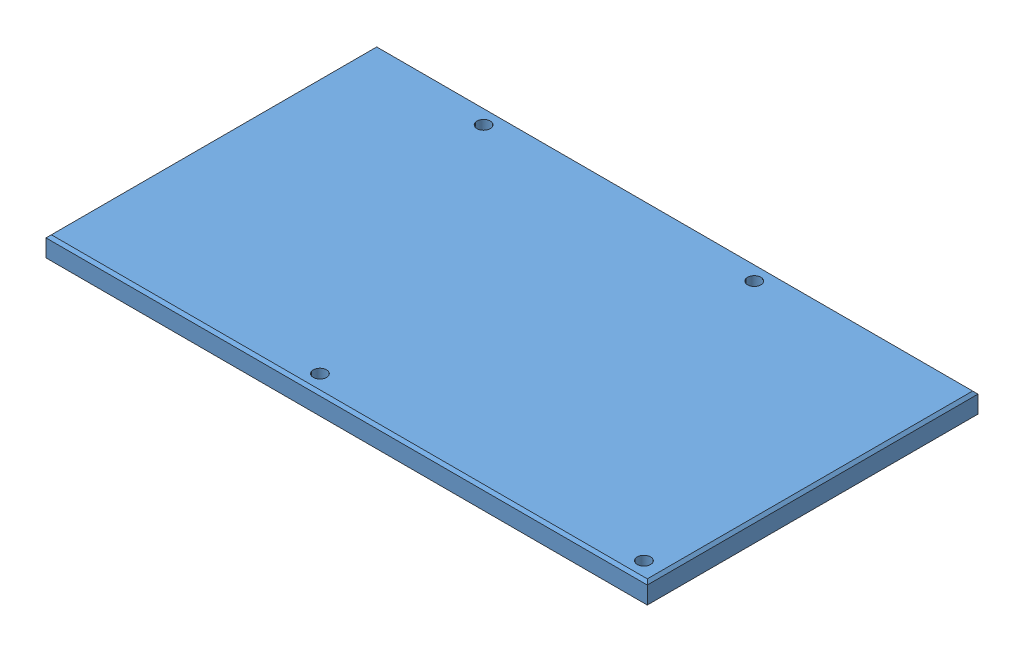
SolidWorks assembly nosilec_napajalnikov, configuration Default. Lengths in mm.
Overall size (180 16 99).
3 component instances, 2 part files, 6 mates.
Components (placement in the parent):
- podstavek_napajalniki-1: podstavek_napajalniki [Default] at (18.8147 123.9174 143.3216) size (180 6 99)
- din_nosilec-1: din_nosilec [Default] at (10.0328 123.9174 164.6273) x (0 0 -1) z (-1 0 0) size (70 10 30)
- din_nosilec-2: din_nosilec [Default] at (100.0328 123.9174 164.6273) x (0 0 -1) z (-1 0 0) size (70 10 30)
Mates (geometry in assembly coordinates):
- Coincident1: coincident anti-aligned: plane of podstavek_napajalniki-1 through (18.8147 123.9174 143.3216) normal (0 -1 0); plane of din_nosilec-1 through (10.0328 123.9174 164.6273) normal (0 1 0)
- Distance1: distance = 14.5 mm aligned: plane of din_nosilec-1 through (15.9698 119.9174 192.8302) normal (0 0 1); plane of podstavek_napajalniki-1 through (-44.0302 129.9174 207.3302) normal (0 0 1)
- Distance3: distance = 30 mm aligned: plane of din_nosilec-1 through (-14.0302 119.9174 192.8302) normal (-1 0 0); plane of podstavek_napajalniki-1 through (-44.0302 129.9174 108.3302) normal (-1 0 0)
- Coincident7: coincident anti-aligned: plane of podstavek_napajalniki-1 through (18.8147 123.9174 143.3216) normal (0 -1 0); plane of din_nosilec-2 through (100.0328 123.9174 164.6273) normal (0 1 0)
- Distance4: distance = 14.5 mm aligned: plane of din_nosilec-2 through (105.9698 119.9174 192.8302) normal (0 0 1); plane of podstavek_napajalniki-1 through (-44.0302 129.9174 207.3302) normal (0 0 1)
- Distance5: distance = 30 mm aligned: plane of din_nosilec-2 through (105.9698 119.9174 192.8302) normal (1 0 0); plane of podstavek_napajalniki-1 through (135.9698 129.9174 108.3302) normal (1 0 0)
